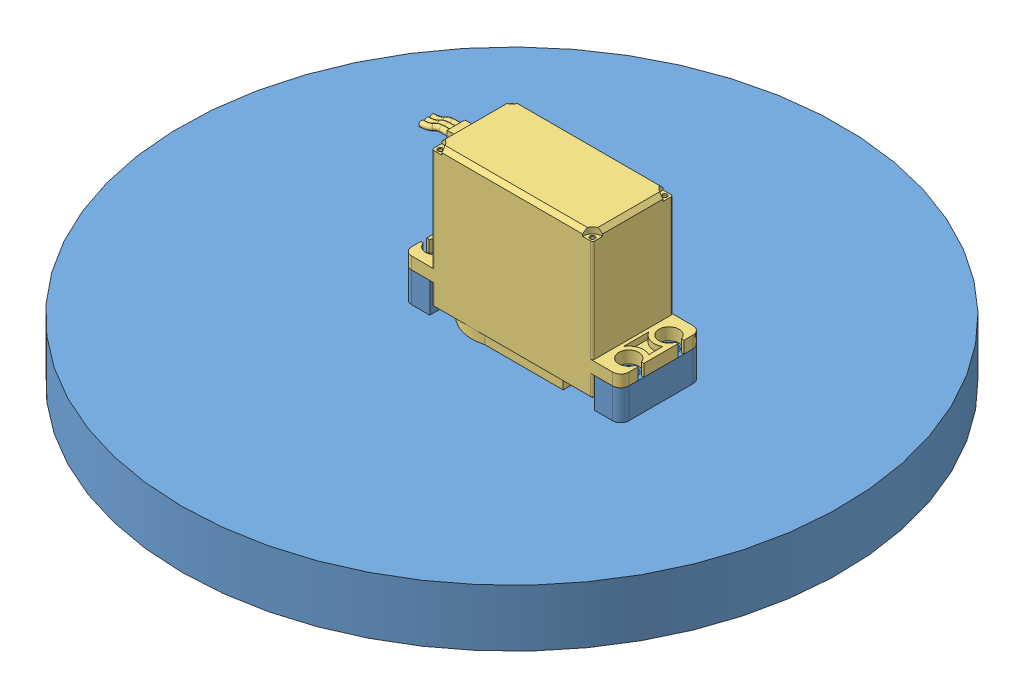
SolidWorks assembly Süpürerek bırakma, configuration Varsayılan. Lengths in mm.
Overall size (164 51.7 164).
3 component instances, 3 part files, 5 mates.
Components (placement in the parent):
- alt tabla-1: alt tabla [Varsayılan] at (-9.0321 24.0507 150) x (-1 0 0) z (0 0 1) size (164 21.7 164)
- kulakçık-1: kulakçık [Varsayılan] at (-9.0321 11.8007 150) x (-0.447144 0 -0.894462) z (0.894462 0 -0.447144) size (87.5 11 22.73)
- TP MG996R-1: TP MG996R [Default] at (1.062 61.5507 150) x (-1 0 0) z (0 0 1) size (58.18 41.75 20)
Mates (geometry in assembly coordinates):
- Concentric1: concentric anti-aligned: cylinder of alt tabla-1 through (-9.0321 22.5507 150) axis (0 1 0) radius 5; cylinder of kulakçık-1 through (-9.0321 22.8007 150) axis (0 -1 0) radius 4.5
- Concentric2: concentric aligned: cylinder of alt tabla-1 through (-9.0321 22.5507 150) axis (0 1 0) radius 5; cylinder of TP MG996R-1 through (-9.0321 23.0507 150) axis (0 1 0) radius 3.5
- Coincident1: coincident anti-aligned: plane of alt tabla-1 through (-9.0321 24.0507 150) normal (0 1 0); plane of TP MG996R-1 through (1.062 24.0507 150) normal (0 -1 0)
- Parallel1: parallel: line of alt tabla-1 through (-16.6305 17.5507 152.1132) axis (-1 0 0); plane of TP MG996R-1 through (21.062 26.5507 160) normal (0 0 1)
- Coincident4: coincident anti-aligned: plane of kulakçık-1 through (-9.0321 19.8007 150) normal (0 1 0); plane of TP MG996R-1 through (1.062 19.8007 150) normal (0 -1 0)
